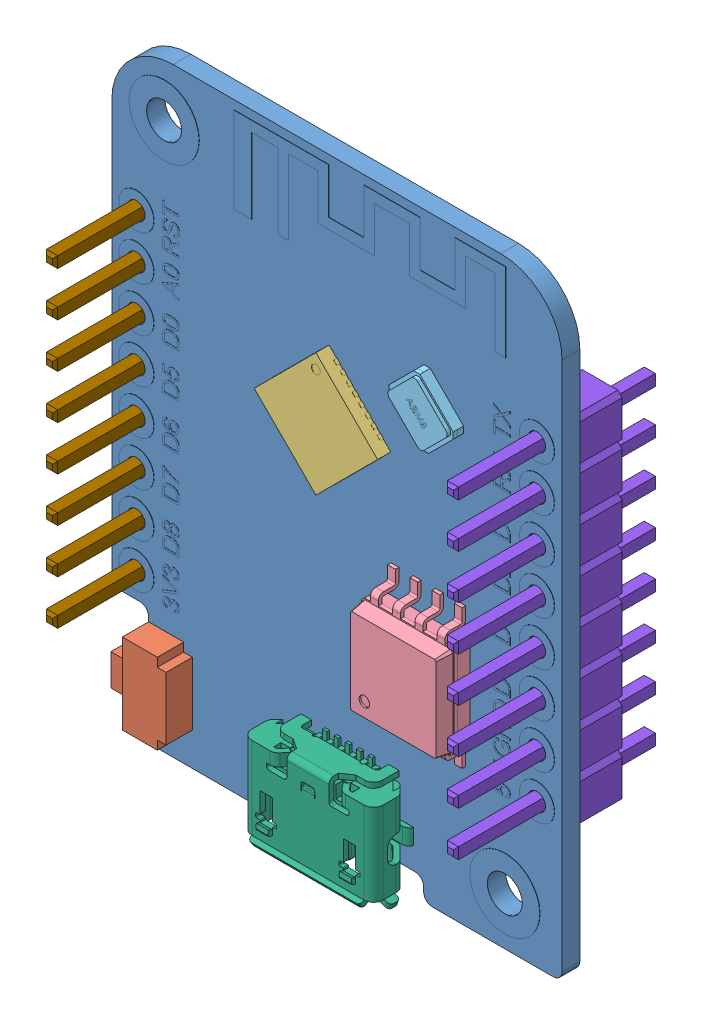
SolidWorks assembly WEMOS_D1_MINI_V3.0.0, configuration Default. Lengths in mm.
Overall size (25.7 34.25 11.54).
9 component instances, 9 part files, 0 mates.
Components (placement in the parent):
- WEMOS_D1_MINI_V_3_0_0_PCB_180112_01-1: WEMOS_D1_MINI_V_3_0_0_PCB_180112_01 [Default] at origin size (25.7 34.25 1.05)
- WEMOS_D1_MINI_V_3_0_0_PUSH_BUTTON_180111_01-1: WEMOS_D1_MINI_V_3_0_0_PUSH_BUTTON_180111_01 [Default] at (-9.5 -13.425 1.258) size (3.5 4.6 1.5)
- QFN_32_1EP_5x5mm_Pitch0_5mm_step1_01-1: QFN_32_1EP_5x5mm_Pitch0_5mm_step1_01 [Default] at (-0.4286 4.2036 0.508) x (0.707107 -0.707107 0) z (0 0 1) size (5 5 0.77)
- SOIJ_8_5_3x5_3mm_Pitch1_27mm_step1_01-1: SOIJ_8_5_3x5_3mm_Pitch1_27mm_step1_01 [Default] at (5.22 -5.255 0.508) x (0 1 0) z (0 0 1) size (7.94 5.3 2.01)
- ABM8_STEP1_01-1: ABM8_STEP1_01 [Default] at (5.4013 7.615 0.5083) x (0.707107 -0.707107 0) z (-0.707107 -0.707107 0) size (3.2 0.8 2.49)
- _050170001_stp1_01-1: _050170001_stp1_01 [Default] at (0.75 -13.975 1.693) x (1 0 0) z (0 -1 0) size (8.2 3.3 5.4)
- SOIC_16_3_9x9_9mm_Pitch1_27mm_step1_01-1: SOIC_16_3_9x9_9mm_Pitch1_27mm_step1_01 [Default] at (-2.85 -5.075 -0.508) x (-1 0 0) z (0 0 -1) size (6 9.9 1.75)
- Pin_Header_Straight_1x08_Pitch2_54mm_step1_01-1: Pin_Header_Straight_1x08_Pitch2_54mm_step1_01 [Default] at (11.44 8.875 -3.0658) size (2.54 20.32 11.54)
- Pin_Header_Straight_1x08_Pitch2_54mm_step1_01001-1: Pin_Header_Straight_1x08_Pitch2_54mm_step1_01001 [Default] at (-11.44 8.875 -3.0658) size (2.54 20.32 11.54)
